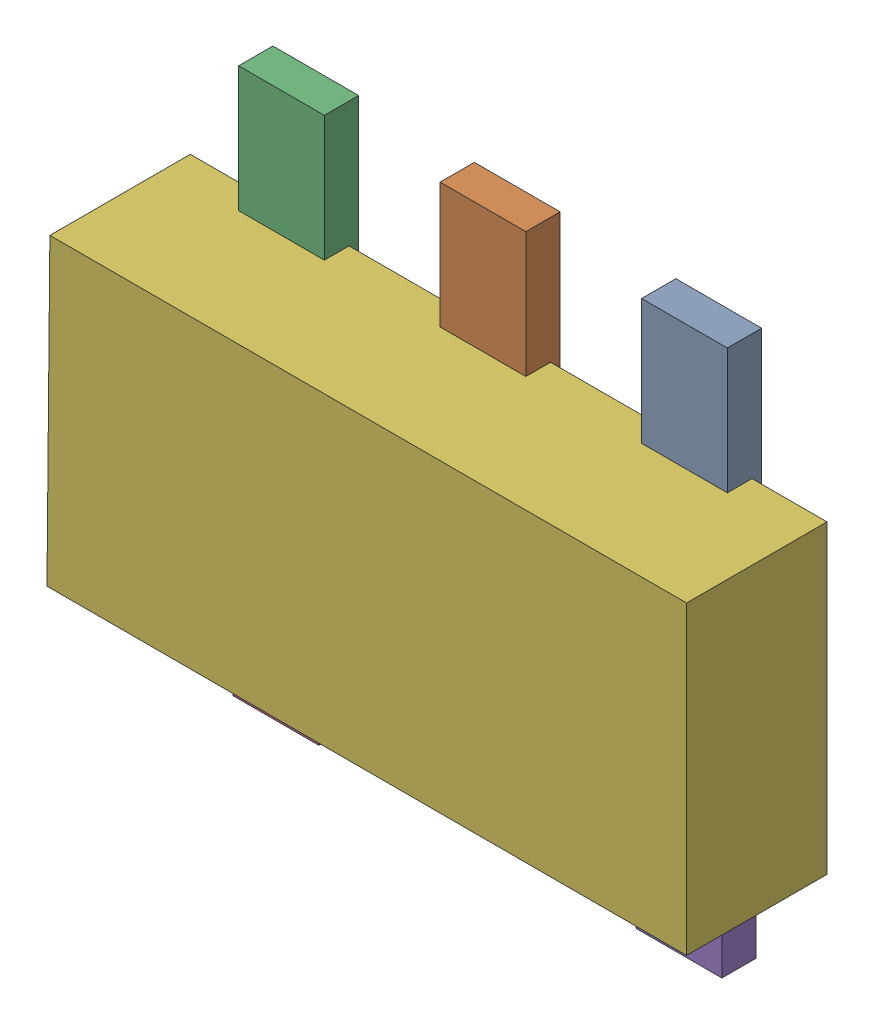
SolidWorks assembly U4, configuration Default. Lengths in mm.
Overall size (2.98 2.56 0.7).
12 component instances, 2 part files, 0 mates.
Components (placement in the parent):
- 744578800-1: 744578800 [Default] at (21.0394 19.6154 0) size (0.4 1.17 0.16)
  - Extruded (42)-1: Extruded (42) [Default] at origin size (0.4 1.17 0.16)
- 744578800_1-1: 744578800_1 [Default] at (20.0996 19.6154 0) size (0.4 1.17 0.16)
  - Extruded (42)-1: Extruded (42) [Default] at origin size (0.4 1.17 0.16)
- 744578800_2-1: 744578800_2 [Default] at (19.1598 19.6154 0) size (0.4 1.17 0.16)
  - Extruded (42)-1: Extruded (42) [Default] at origin size (0.4 1.17 0.16)
- 744578800_3-1: 744578800_3 [Default] at (19.1344 18.2262 0) size (0.4 1.17 0.16)
  - Extruded (42)-1: Extruded (42) [Default] at origin size (0.4 1.17 0.16)
- 744578800_4-1: 744578800_4 [Default] at (21.014 18.2262 0) size (0.4 1.17 0.16)
  - Extruded (42)-1: Extruded (42) [Default] at origin size (0.4 1.17 0.16)
- 1550848384-1: 1550848384 [Default] at (20.0977 18.9027 0.045) size (2.98 1.42 0.65)
  - Extruded (43)-1: Extruded (43) [Default] at origin size (2.98 1.42 0.65)
